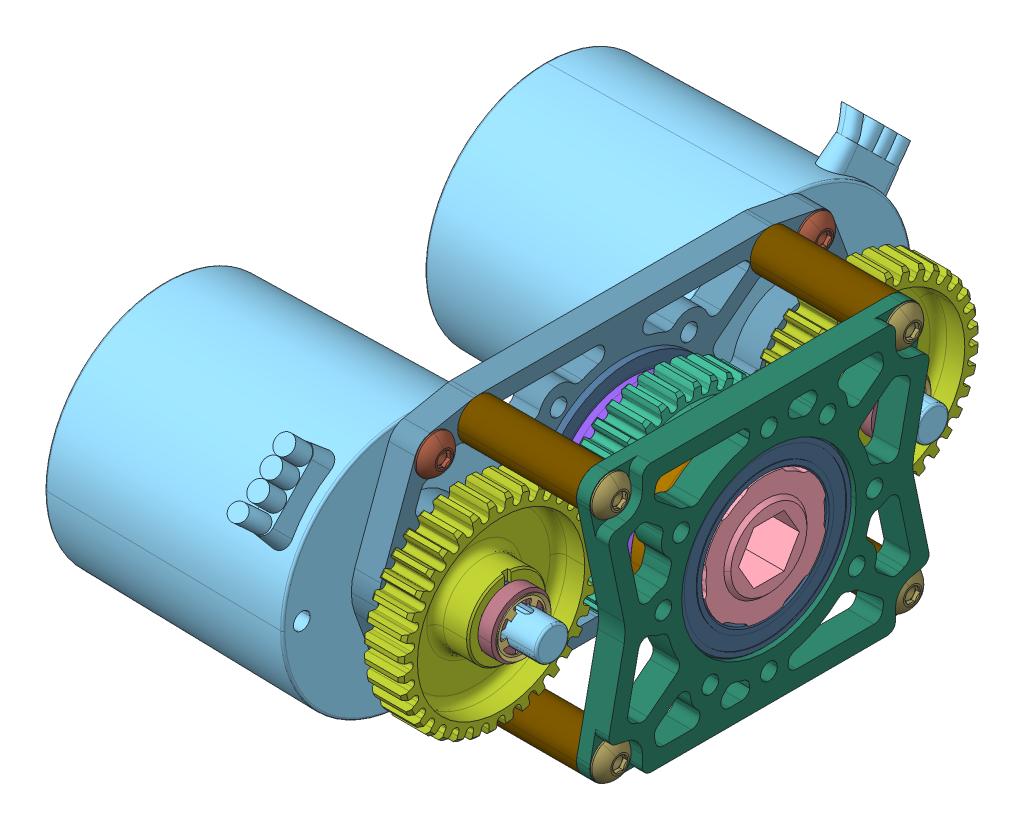
SolidWorks assembly REV-21-2099 1-to-1, configuration Default. Lengths in mm.
Overall size (99.54 69.01 161.62).
40 component instances, 18 part files, 0 mates.
Components (placement in the parent):
- REV-21-2099 1-to-1.STEP-1: REV-21-2099 1-to-1.STEP [Default] at origin size (99.54 69.01 161.62)
  - REV-21-1879_For Motor Shaft, One Clip (Spaced 0.150).STEP-1: REV-21-1879_For Motor Shaft, One Clip (Spaced 0.150).STEP [Default] at (3.5 0 45.72) x (0 0 -1) z (1 0 0) size (13 13.75 24.57)
    - REV-21-1879.STEP-1: REV-21-1879.STEP [Default] at origin size (12.7 13.75 20)
    - Key_2mm_20mmLong.STEP-1: Key_2mm_20mmLong.STEP [Default] at (0.0325 4.05 10) x (0 0 -1) z (0 1 0) size (20 2 2)
    - Retaining_Ring_8mm.STEP-1: Retaining_Ring_8mm.STEP [Default] at (0 0 24.185) x (-1 0 0) z (0 0 1) size (13 13 0.76)
  - REV-21-1879_For Motor Shaft, One Clip (Spaced 0.150).STEP-2: REV-21-1879_For Motor Shaft, One Clip (Spaced 0.150).STEP [Default] at (3.5 0 -45.72) x (0 -1 0) z (1 0 0) size (13 13.75 24.57)
    - REV-21-1879.STEP-1: REV-21-1879.STEP [Default] at origin size (12.7 13.75 20)
    - Key_2mm_20mmLong.STEP-1: Key_2mm_20mmLong.STEP [Default] at (0.0325 4.05 10) x (0 0 -1) z (0 1 0) size (20 2 2)
    - Retaining_Ring_8mm.STEP-1: Retaining_Ring_8mm.STEP [Default] at (0 0 24.185) x (-1 0 0) z (0 0 1) size (13 13 0.76)
  - REV-21-2079.STEP-1: REV-21-2079.STEP [Default] at (20.6375 0 0) size (41.27 34.92 32.55)
  - REV-21-1650.STEP-1: REV-21-1650.STEP [Default] at (0 0 -45.72) x (0 -1 0) z (1 0 0) size (65.4 64.76 93.26)
  - REV-21-1650.STEP-2: REV-21-1650.STEP [Default] at (0 0 45.72) x (0 0 -1) z (1 0 0) size (65.4 64.76 93.26)
  - REV-21-3012.STEP-1: REV-21-3012.STEP [Default] at (17.375 0 0) x (0 1 0) z (1 0 0) size (48.1 48.1 12.7)
  - REV-21-1929.STEP-1: REV-21-1929.STEP [Default] at (17.7875 0 45.72) x (0 0 1) z (-1 0 0) size (48.2 48.2 12.7)
  - REV-21-1929.STEP-2: REV-21-1929.STEP [Default] at (17.7875 0 -45.72) x (0 -0.5 0.866025) z (-1 0 0) size (48.2 48.2 12.7)
  - REV-21-2541.STEP-1: REV-21-2541.STEP [Default] at (9.4375 0 0) x (0 0 -1) z (1 0 0) size (38.1 38.1 3.17)
  - REV-21-2541.STEP-2: REV-21-2541.STEP [Default] at (25.4875 0 0) x (0 0 -1) z (1 0 0) size (38.1 38.1 3.17)
  - REV-21-2542.STEP-1: REV-21-2542.STEP [Default] at (30.25 0 0) x (0 0 1) z (-1 0 0) size (38.1 38.1 6.35)
  - F6806ZZ.STEP-1: F6806ZZ.STEP [Default] at (4.35 0 0) x (0 -0.419542 0.907736) z (-1 0 0) size (45 45 7)
  - F6806ZZ.STEP-2: F6806ZZ.STEP [Default] at (36.925 0 0) x (0 -0.734429 0.678686) z (1 0 0) size (45 45 7)
  - #10 Button Head Cap Screws_0.500 Long.STEP-1: #10 Button Head Cap Screws_0.500 Long.STEP [Default] at (1.2827 25.4 45.72) x (0 0.07794 -0.996958) z (1 0 0) size (9.17 9.17 15.27)
  - #10 Button Head Cap Screws_0.500 Long.STEP-2: #10 Button Head Cap Screws_0.500 Long.STEP [Default] at (1.2827 -25.4 45.72) x (0 0.235024 -0.971989) z (1 0 0) size (9.17 9.17 15.27)
  - #10 Button Head Cap Screws_0.500 Long.STEP-3: #10 Button Head Cap Screws_0.500 Long.STEP [Default] at (1.2827 25.4 -45.72) x (0 0.356877 -0.934151) z (1 0 0) size (9.17 9.17 15.27)
  - #10 Button Head Cap Screws_0.500 Long.STEP-4: #10 Button Head Cap Screws_0.500 Long.STEP [Default] at (1.2827 -25.4 -45.72) x (0 0.442397 -0.896819) z (1 0 0) size (9.17 9.17 15.27)
  - #10 Button Head Cap Screws_1.500 Long.STEP-1: #10 Button Head Cap Screws_1.500 Long.STEP [Default] at (20.3327 27.454 35.2002) x (0 -0.07794 0.996958) z (1 0 0) size (9.17 9.17 40.67)
  - #10 Button Head Cap Screws_1.500 Long.STEP-2: #10 Button Head Cap Screws_1.500 Long.STEP [Default] at (20.3327 27.454 -35.2002) x (0 -0.235024 0.971989) z (1 0 0) size (9.17 9.17 40.67)
  - #10 Button Head Cap Screws_1.500 Long.STEP-3: #10 Button Head Cap Screws_1.500 Long.STEP [Default] at (20.3327 -27.454 -35.2002) x (0 -0.356877 0.934151) z (1 0 0) size (9.17 9.17 40.67)
  - #10 Button Head Cap Screws_1.500 Long.STEP-4: #10 Button Head Cap Screws_1.500 Long.STEP [Default] at (20.3327 -27.454 35.2002) x (0 -0.442397 0.896819) z (1 0 0) size (9.17 9.17 40.67)
  - REV-21-2078.STEP-1: REV-21-2078.STEP [Default] at (25.725 0 45.72) x (0 0 1) z (-1 0 0) size (14.29 14.29 3.17)
  - REV-21-2078.STEP-2: REV-21-2078.STEP [Default] at (25.725 0 -45.72) x (0 1 0) z (-1 0 0) size (14.29 14.29 3.17)
  - REV-21-2099-P01.STEP-1: REV-21-2099-P01.STEP [Default] at origin size (6.35 64.43 118.43)
  - REV-21-2099-P02.STEP-1: REV-21-2099-P02.STEP [Default] at (34.925 0 0) size (6.35 64.43 79.93)
  - REV-21-2005.STEP-1: REV-21-2005.STEP [Default] at (6.675 0 45.72) x (0 0 -1) z (1 0 0) size (18.29 18.29 6.35)
  - REV-21-2003.STEP-1: REV-21-2003.STEP [Default] at (10.6438 0 45.72) x (0 0 -1) z (1 0 0) size (18.29 18.29 1.59)
  - REV-21-2003.STEP-2: REV-21-2003.STEP [Default] at (10.6438 0 -45.72) x (0 0 -1) z (1 0 0) size (18.29 18.29 1.59)
  - REV-21-2005.STEP-2: REV-21-2005.STEP [Default] at (6.675 0 -45.72) x (0 0 -1) z (1 0 0) size (18.29 18.29 6.35)
  - #10 Unthreaded Spacers_1.125in Long.STEP-1: #10 Unthreaded Spacers_1.125in Long.STEP [Default] at (20.6375 27.454 35.2002) size (28.57 9.53 9.53)
  - #10 Unthreaded Spacers_1.125in Long.STEP-2: #10 Unthreaded Spacers_1.125in Long.STEP [Default] at (20.6375 -27.454 35.2002) size (28.57 9.53 9.53)
  - #10 Unthreaded Spacers_1.125in Long.STEP-3: #10 Unthreaded Spacers_1.125in Long.STEP [Default] at (20.6375 27.454 -35.2002) size (28.57 9.53 9.53)
  - #10 Unthreaded Spacers_1.125in Long.STEP-4: #10 Unthreaded Spacers_1.125in Long.STEP [Default] at (20.6375 -27.454 -35.2002) size (28.57 9.53 9.53)
